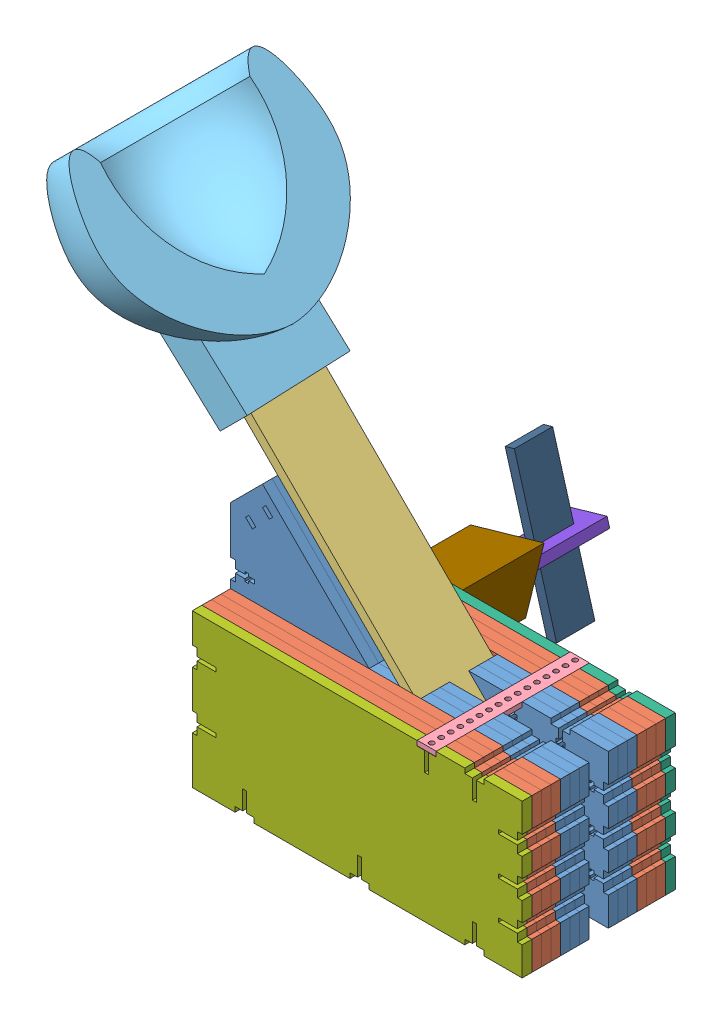
SolidWorks assembly Assem1, configuration Default. Lengths in mm.
Overall size (357.21 344.88 256.5).
21 component instances, 10 part files, 50 mates.
Components (placement in the parent):
- partmid-1: partmid [Default] at (62.3458 26.7097 166.7378) size (218.9 172.29 6.35)
- partmid-2: partmid [Default] at (62.3458 26.7097 173.0878) size (218.9 172.29 6.35)
- partmid-3: partmid [Default] at (62.3458 26.7097 179.4378) size (218.9 172.29 6.35)
- partmid-6: partmid [Default] at (62.3458 26.7097 198.4878) size (218.9 172.29 6.35)
- partmid-7: partmid [Default] at (62.3458 26.7097 204.8378) size (218.9 172.29 6.35)
- partmid-8: partmid [Default] at (62.3458 26.7097 211.1878) size (218.9 172.29 6.35)
- topmid-1: topmid [Default] at (61.5386 26.7097 160.3878) size (218.9 101.6 6.35) (hidden)
- topmid-2: topmid [Default] at (62.3458 26.7097 217.5378) size (218.9 101.6 6.35)
- arm-1: arm [Default] at (-25.5227 236.389 217.5378) x (0.707107 -0.707107 0) z (0 0 1) size (254 6.35 50.8)
- topmid-3: topmid [Default] at (62.3458 26.7097 160.3878) size (218.9 101.6 6.35)
- connector-3: connector [Default] at (119.4958 125.1347 141.136) x (0 0 1) z (0 1 0) size (101.6 12.7 3.17)
- spoon2-2: spoon2 [Default] at (-87.2417 347.4349 158.4946) x (0 0 1) z (0.707107 -0.707107 0) size (159.7 79.85 163.48)
- topmid-4: topmid [Default] at (62.3458 26.7097 154.0378) size (218.9 101.6 6.35)
- topmid-5: topmid [Default] at (62.3458 26.7097 147.6878) size (218.9 101.6 6.35)
- toplever-1: toplever [Default] at (62.3458 26.7097 141.3378) size (218.9 101.6 6.35)
- topmid-6: topmid [Default] at (62.3458 26.7097 223.8878) size (218.9 101.6 6.35)
- topmid-7: topmid [Default] at (62.3458 26.7097 230.2378) size (218.9 101.6 6.35)
- top-3: top [Default] at (62.3458 26.7097 236.5878) size (218.9 101.6 6.35)
- leverarm1-1: leverarm1 [Default] at (-5.5871 78.5081 14.3378) x (0 0 1) z (-0.961183 -0.275911 0) size (76.2 6.35 25.4)
- leverbit-2: leverbit [Default] at (13.8362 56.873 65.1378) x (0.961183 0.275911 0) z (0.275911 -0.961183 0) size (50.8 82.55 43.99)
- leverarm2-1: leverarm2 [Default] at (21.6918 40.0935 52.4378) x (0 0 -1) z (0.961183 0.275911 0) size (25.4 101.6 6.35)
Mates (geometry in assembly coordinates):
- Coincident1: coincident: plane of partmid-1 through (62.3458 26.7097 173.0878) normal (0 0 1); plane of partmid-2 through (62.3458 26.7097 173.0878) normal (0 0 -1)
- Coincident7: coincident: plane of partmid-1 through (189.3458 128.3097 173.0878) normal (0 1 0); plane of partmid-2 through (189.3458 128.3097 179.4378) normal (0 1 0)
- Coincident8: coincident: plane of partmid-1 through (189.3458 26.7097 173.0878) normal (1 0 0); plane of partmid-2 through (189.3458 26.7097 179.4378) normal (1 0 0)
- Coincident9: coincident: plane of partmid-2 through (62.3458 26.7097 179.4378) normal (0 0 1); plane of partmid-3 through (62.3458 26.7097 179.4378) normal (0 0 -1)
- Coincident10: coincident: plane of partmid-2 through (189.3458 26.7097 179.4378) normal (1 0 0); plane of partmid-3 through (189.3458 26.7097 185.7878) normal (1 0 0)
- Coincident11: coincident: plane of partmid-2 through (189.3458 128.3097 179.4378) normal (0 1 0); plane of partmid-3 through (189.3458 128.3097 185.7878) normal (0 1 0)
- Coincident21: coincident: plane of partmid-6 through (62.3458 26.7097 204.8378) normal (0 0 1); plane of partmid-7 through (62.3458 26.7097 204.8378) normal (0 0 -1)
- Coincident22: coincident: plane of partmid-6 through (62.3458 128.3097 204.8378) normal (0.707107 0.707107 0); plane of partmid-7 through (62.3458 128.3097 211.1878) normal (0.707107 0.707107 0)
- Coincident23: coincident: plane of partmid-6 through (189.3458 26.7097 204.8378) normal (1 0 0); plane of partmid-7 through (189.3458 26.7097 211.1878) normal (1 0 0)
- Coincident24: coincident: plane of partmid-7 through (62.3458 26.7097 211.1878) normal (0 0 1); plane of partmid-8 through (62.3458 26.7097 211.1878) normal (0 0 -1)
- Coincident25: coincident: plane of partmid-7 through (189.3458 26.7097 211.1878) normal (1 0 0); plane of partmid-8 through (189.3458 26.7097 217.5378) normal (1 0 0)
- Coincident26: coincident: plane of partmid-7 through (189.3458 128.3097 211.1878) normal (0 1 0); plane of partmid-8 through (189.3458 128.3097 217.5378) normal (0 1 0)
- Coincident32: coincident: plane of partmid-1 through (62.3458 26.7097 166.7378) normal (0 0 -1); plane of topmid-1 through (61.5386 26.7097 166.7378) normal (0 0 1)
- Coincident33: coincident: plane of partmid-1 through (189.3458 128.3097 173.0878) normal (0 1 0); plane of topmid-1 through (188.5386 128.3097 166.7378) normal (0 1 0)
- Coincident34: coincident: plane of partmid-8 through (62.3458 26.7097 217.5378) normal (0 0 1); plane of topmid-2 through (62.3458 26.7097 217.5378) normal (0 0 -1)
- Coincident35: coincident: plane of partmid-8 through (189.3458 128.3097 217.5378) normal (0 1 0); plane of topmid-2 through (189.3458 128.3097 223.8878) normal (0 1 0)
- Coincident36: coincident: plane of partmid-8 through (189.3458 26.7097 217.5378) normal (1 0 0); plane of topmid-2 through (189.3458 26.7097 223.8878) normal (1 0 0)
- Coincident41: coincident: plane of partmid-1 through (62.3458 26.7097 166.7378) normal (0 0 -1); plane of arm-1 through (-21.0326 240.8791 166.7378) normal (0 0 -1)
- Coincident47: coincident: plane of partmid-1 through (62.3458 26.7097 166.7378) normal (0 0 -1); plane of topmid-3 through (62.3458 26.7097 166.7378) normal (0 0 1)
- Coincident48: coincident: line of partmid-2 through (-29.551 58.1317 173.0878) axis (0 -1 0); plane of topmid-3 through (-29.551 177.7976 166.7378) normal (-1 0 0)
- Coincident49: coincident: plane of partmid-1 through (189.3458 128.3097 173.0878) normal (0 1 0); plane of topmid-3 through (189.3458 128.3097 166.7378) normal (0 1 0)
- Coincident55: coincident: plane of topmid-3 through (62.3458 125.1347 287.3878) normal (0 1 0); plane of connector-3 through (119.4958 125.1347 141.136) normal (0 -1 0)
- Coincident61: coincident: plane of arm-1 through (-25.5227 236.389 217.5378) normal (-0.707107 -0.707107 0); plane of spoon2-2 through (-66.6231 277.4893 168.4415) normal (0.707107 0.707107 0)
- Coincident62: coincident: plane of topmid-3 through (62.3458 26.7097 160.3878) normal (0 0 -1); plane of topmid-4 through (62.3458 26.7097 160.3878) normal (0 0 1)
- Coincident63: coincident: plane of topmid-3 through (189.3458 128.3097 166.7378) normal (0 1 0); plane of topmid-4 through (189.3458 128.3097 160.3878) normal (0 1 0)
- Coincident64: coincident: plane of topmid-4 through (62.3458 26.7097 154.0378) normal (0 0 -1); plane of topmid-5 through (62.3458 26.7097 154.0378) normal (0 0 1)
- Coincident65: coincident: plane of topmid-4 through (189.3458 128.3097 160.3878) normal (0 1 0); plane of topmid-5 through (189.3458 128.3097 154.0378) normal (0 1 0)
- Coincident66: coincident: plane of topmid-4 through (189.3458 26.7097 160.3878) normal (1 0 0); plane of topmid-5 through (189.3458 26.7097 154.0378) normal (1 0 0)
- Coincident67: coincident: plane of topmid-5 through (62.3458 26.7097 147.6878) normal (0 0 -1); plane of toplever-1 through (62.3458 26.7097 147.6878) normal (0 0 1)
- Coincident68: coincident: plane of topmid-5 through (189.3458 128.3097 154.0378) normal (0 1 0); plane of toplever-1 through (189.3458 128.3097 147.6878) normal (0 1 0)
- Coincident69: coincident: plane of topmid-5 through (189.3458 26.7097 154.0378) normal (1 0 0); plane of toplever-1 through (189.3458 26.7097 147.6878) normal (1 0 0)
- Coincident70: coincident: plane of topmid-2 through (62.3458 26.7097 223.8878) normal (0 0 1); plane of topmid-6 through (62.3458 26.7097 223.8878) normal (0 0 -1)
- Coincident71: coincident: plane of topmid-2 through (189.3458 128.3097 223.8878) normal (0 1 0); plane of topmid-6 through (189.3458 128.3097 230.2378) normal (0 1 0)
- Coincident72: coincident: plane of topmid-2 through (189.3458 26.7097 223.8878) normal (1 0 0); plane of topmid-6 through (189.3458 26.7097 230.2378) normal (1 0 0)
- Coincident73: coincident: plane of topmid-6 through (62.3458 26.7097 230.2378) normal (0 0 1); plane of topmid-7 through (62.3458 26.7097 230.2378) normal (0 0 -1)
- Coincident74: coincident: plane of topmid-6 through (189.3458 128.3097 230.2378) normal (0 1 0); plane of topmid-7 through (189.3458 128.3097 236.5878) normal (0 1 0)
- Coincident75: coincident: plane of topmid-6 through (189.3458 26.7097 230.2378) normal (1 0 0); plane of topmid-7 through (189.3458 26.7097 236.5878) normal (1 0 0)
- Coincident78: coincident: plane of topmid-7 through (62.3458 26.7097 236.5878) normal (0 0 1); plane of top-3 through (62.3458 26.7097 236.5878) normal (0 0 -1)
- Coincident79: coincident: plane of topmid-7 through (189.3458 26.7097 236.5878) normal (1 0 0); plane of top-3 through (189.3458 26.7097 242.9378) normal (1 0 0)
- Coincident80: coincident: plane of topmid-7 through (189.3458 128.3097 236.5878) normal (0 1 0); plane of top-3 through (189.3458 128.3097 242.9378) normal (0 1 0)
- Coincident81: coincident: plane of topmid-3 through (-29.551 177.7976 166.7378) normal (-1 0 0); plane of topmid-4 through (-29.551 177.7976 160.3878) normal (-1 0 0)
- Concentric3: concentric: cylinder of toplever-1 through (5.7439 85.0639 11.7978) axis (0 0 1) radius 10.795; cylinder of leverbit-2 through (5.7439 85.0639 147.6878) axis (0 0 -1) radius 4.064
- Coincident86: coincident: plane of toplever-1 through (62.3458 26.7097 141.3378) normal (0 0 -1); plane of leverbit-2 through (13.8362 56.873 141.3378) normal (0 0 1)
- Coincident87: coincident: plane of leverarm1-1 through (-7.3391 84.6116 90.5378) normal (0 0 1); plane of leverbit-2 through (13.8362 56.873 90.5378) normal (0 0 -1)
- Coincident88: coincident: plane of leverarm1-1 through (-7.3391 84.6116 14.3378) normal (-0.275911 0.961183 0); plane of leverbit-2 through (17.0749 91.6198 90.5378) normal (0.275911 -0.961183 0)
- Coincident89: coincident: plane of leverarm1-1 through (-7.3391 84.6116 14.3378) normal (-0.961183 -0.275911 0); plane of leverbit-2 through (-5.5871 78.5081 90.5378) normal (0.961183 0.275911 0)
- Coincident91: coincident: plane of leverarm1-1 through (7.6755 88.9216 52.4378) normal (0 0 -1); plane of leverarm2-1 through (-6.3407 137.7497 52.4378) normal (0 0 1)
- Coincident92: coincident: plane of leverarm1-1 through (7.6755 88.9216 27.0378) normal (0 0 1); plane of leverarm2-1 through (-6.3407 137.7497 27.0378) normal (0 0 -1)
- Coincident93: coincident: plane of leverarm1-1 through (1.572 87.1696 27.0378) normal (0.961183 0.275911 0); plane of leverarm2-1 through (-12.4443 135.9977 52.4378) normal (-0.961183 -0.275911 0)
- Distance1: distance = 44.45 mm: plane of leverarm2-1 through (21.6918 40.0935 52.4378) normal (0.275911 -0.961183 0); plane of leverarm1-1 through (-5.5871 78.5081 14.3378) normal (0.275911 -0.961183 0)
